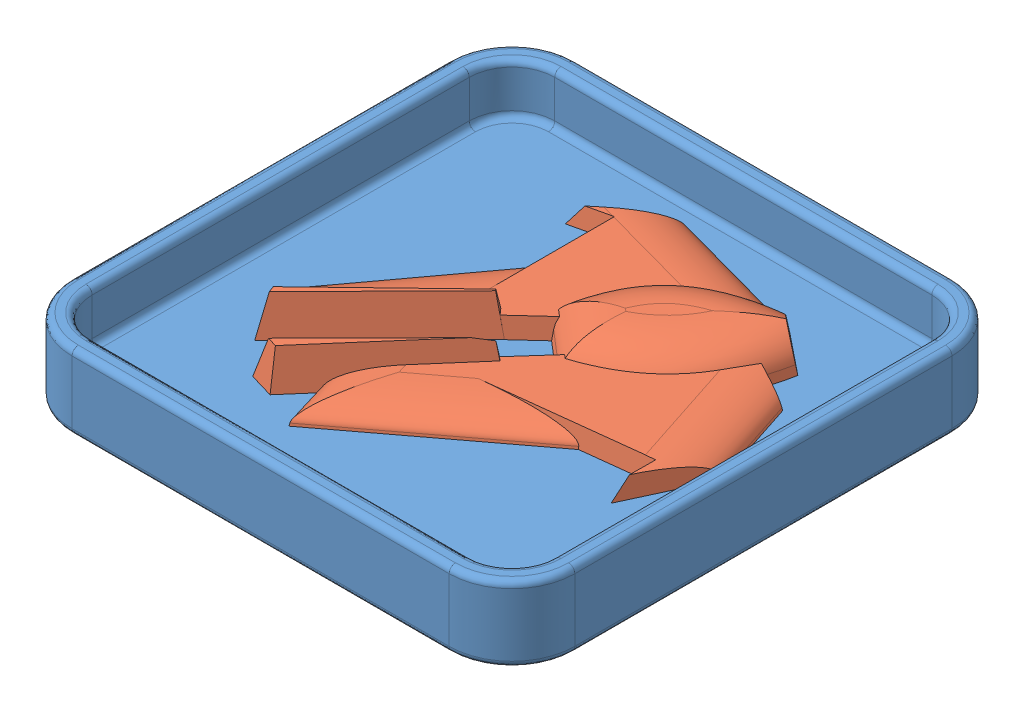
SolidWorks assembly RedSpaceShip, configuration Default. Lengths in mm.
Overall size (40 6 40).
2 component instances, 2 part files, 2 mates.
Components (placement in the parent):
- Tile-1: Tile [Default] at (17.6914 18.649 30.7585) size (40 6 40)
- RedSpaceShip-1: RedSpaceShip [Default] at (17.6633 20.649 30.3585) size (31.19 3.02 29.95)
Mates (geometry in assembly coordinates):
- Coincident1: coincident anti-aligned: plane of Tile-1 through (2.6914 20.649 45.7585) normal (0 1 0); plane of RedSpaceShip-1 through (17.6633 20.649 30.3585) normal (0 -1 0)
- Coincident2: coincident anti-aligned: line of Tile-1 through (32.6914 20.649 12.8585) axis (-1 0 0); line of RedSpaceShip-1 through (0.1633 20.649 12.8585) axis (1 0 0)
